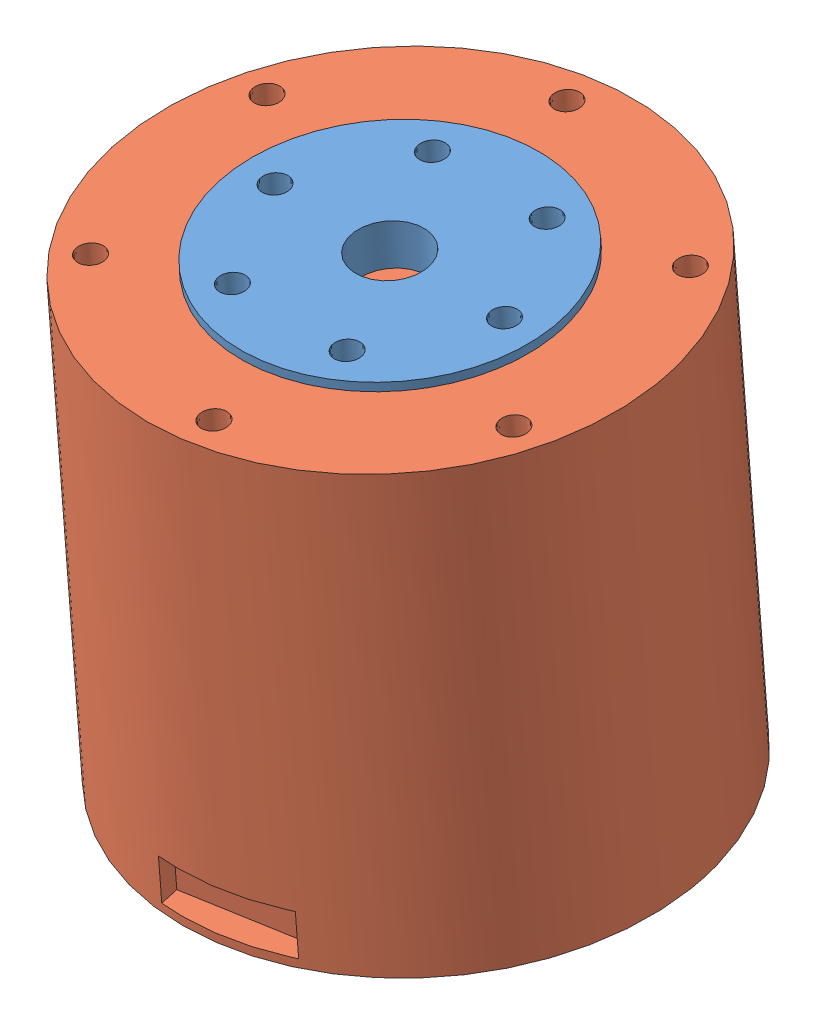
SolidWorks assembly 4340电机装配体, configuration 默认. Lengths in mm.
Overall size (65.31 58.53 69.21).
2 component instances, 2 part files, 2 mates.
Components (placement in the parent):
- 4340电机转子-1: 4340电机转子 [默认] at (-2.9199 39.3197 92.1187) x (0.868408 0.03882 -0.494328) z (-0.000491 0.996998 0.077432) size (35 35 5)
- 4340电机定子-1: 4340电机定子 [默认] at (-2.8957 -9.8323 88.3013) x (0.987466 0.012704 -0.157317) z (-0.000491 0.996998 0.077432) size (57 57 53.3)
Mates (geometry in assembly coordinates):
- 重合1: coincident anti-aligned: plane of 4340电机转子-1 through (-2.9199 39.3197 92.1187) normal (0.000491 -0.996998 -0.077432); plane of 电机定子-1 through (-2.9199 39.3197 92.1187) normal (-0.000491 0.996998 0.077432)
- 同心1: concentric aligned: circle of 电机转子-1; circle of 电机定子-1
